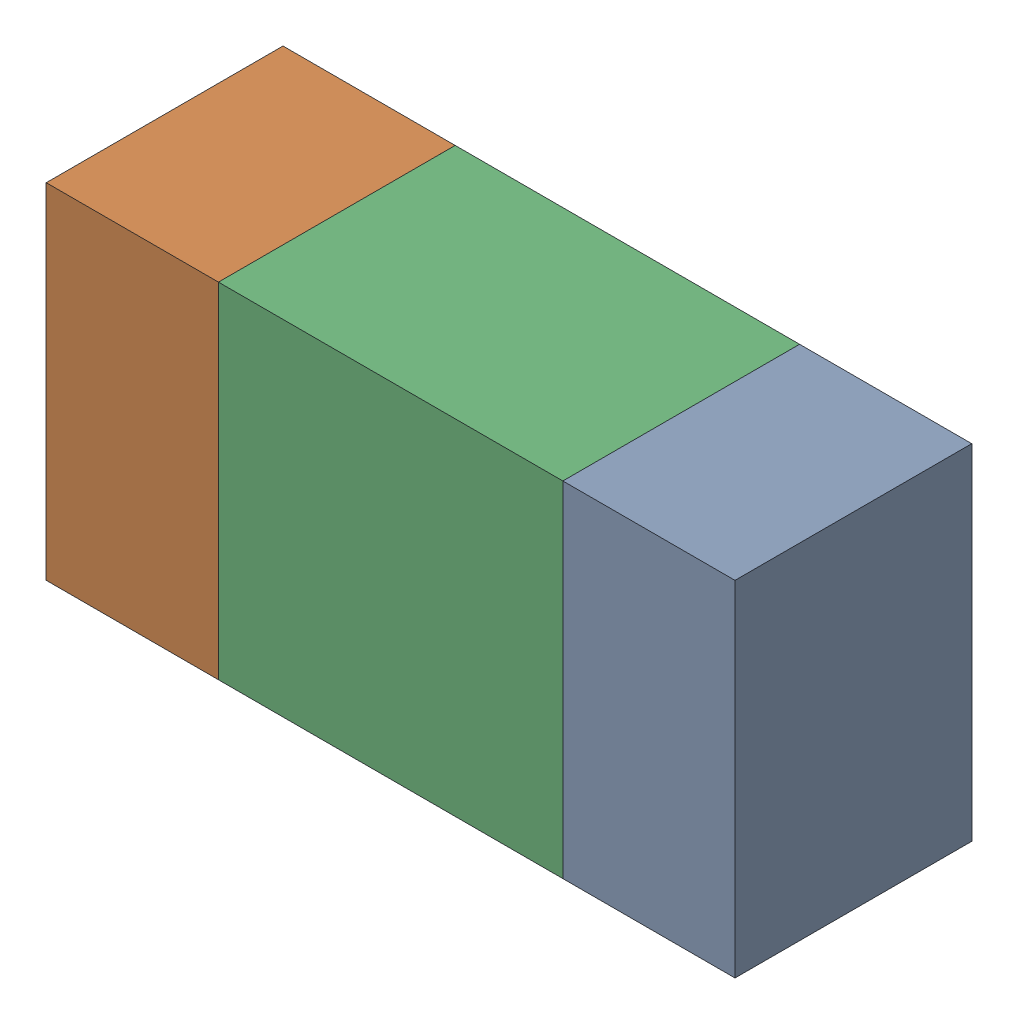
SolidWorks assembly R82, configuration ﾃﾞﾌｫﾙﾄ. Lengths in mm.
Overall size (1.6 0.8 0.55).
6 component instances, 2 part files, 0 mates.
Components (placement in the parent):
- 689261512-1: 689261512 [ﾃﾞﾌｫﾙﾄ] at (23.0999 50.0001 -1.7503) size (0.4 0.8 0.55)
  - Extruded_32-1: Extruded_32 [ﾃﾞﾌｫﾙﾄ] at origin size (0.4 0.8 0.55)
- 689261512-2: 689261512 [ﾃﾞﾌｫﾙﾄ] at (21.8999 50.0001 -1.7503) size (0.4 0.8 0.55)
  - Extruded_32-1: Extruded_32 [ﾃﾞﾌｫﾙﾄ] at origin size (0.4 0.8 0.55)
- 689261648-1: 689261648 [ﾃﾞﾌｫﾙﾄ] at (22.5 50.0001 -1.7503) size (0.8 0.8 0.55)
  - Extruded_33-1: Extruded_33 [ﾃﾞﾌｫﾙﾄ] at origin size (0.8 0.8 0.55)
